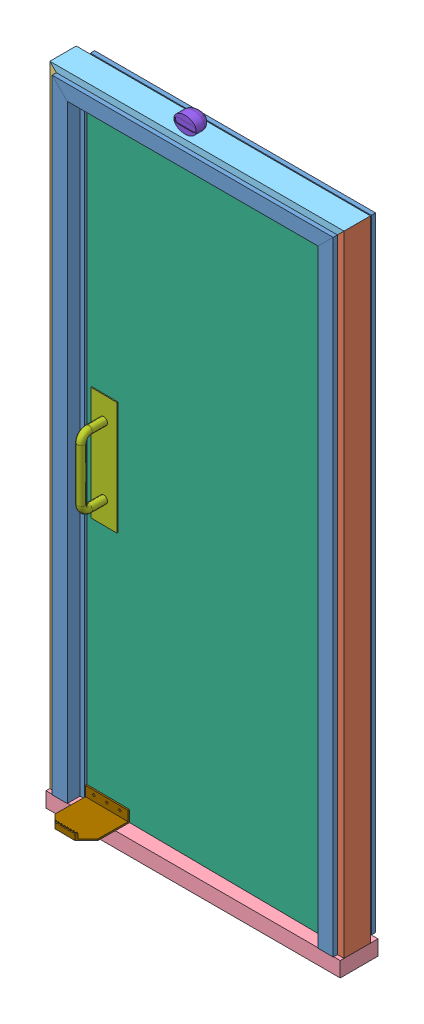
SolidWorks assembly Door 32, configuration Default. Lengths in mm.
Overall size (990.6 2284.92 238.36).
9 component instances, 9 part files, 24 mates.
Components (placement in the parent):
- Door Frame-1: Door Frame [Default] at (342.7653 -62.8092 1731.374) size (946.15 2098.68 142.88)
- Steel Tube Right-1: Steel Tube Right [Default] at (1180.9653 -62.8092 1671.049) size (63.5 2120.9 88.9)
- Steel Tube Left-1: Steel Tube Left [Default] at (253.8653 -62.8092 1671.049) size (63.5 2120.9 88.9)
- Steel Tube Base-1: Steel Tube Base [Default] at (253.8653 -113.6092 1772.649) size (990.6 50.8 127)
- Steel Tube Top-1: Steel Tube Top [Default] at (317.3653 1994.5908 1671.049) size (990.6 63.5 88.9)
- Door-1: Door [Default] at (-417.305 -65.202 1671.7811) x (0.999954 0 0.009626) z (-0.009626 0 0.999954) size (812.8 2032 44.45)
- DOOR32_HNDL-1: DOOR32_HNDL [Default] at (403.1251 953.1908 1724.1309) x (0.999954 0 0.009626) z (-0.009626 0 0.999954) size (88.9 381 139.7)
- Low Profile Forklift Red Light-1: Low Profile Forklift Red Light [Default] at (749.1653 2140.6408 1746.741) size (75.19 61.34 53.09)
- StepNPull-1: StepNPull [Default] at (342.8029 -62.8092 1723.5502) x (0.999954 0 0.009626) z (-0.009626 0 0.999954) size (144.78 38.1 144.78)
Mates (geometry in assembly coordinates):
- Coincident1: coincident anti-aligned: plane of Door Frame-1 through (317.3653 -62.8092 1645.649) normal (-1 0 0); plane of Steel Tube Left-1 through (317.3653 1994.5908 1759.949) normal (1 0 0)
- Coincident2: coincident anti-aligned: plane of Door Frame-1 through (1180.9653 2042.6333 1645.649) normal (1 0 0); plane of Steel Tube Right-1 through (1180.9653 -62.8092 1759.949) normal (-1 0 0)
- Coincident3: coincident anti-aligned: plane of Door Frame-1 through (1180.9653 2042.6333 1759.949) normal (0 0 -1); plane of Steel Tube Right-1 through (1180.9653 -62.8092 1759.949) normal (0 0 1)
- Coincident4: coincident anti-aligned: plane of Door Frame-1 through (269.3228 1994.5908 1645.649) normal (0 1 0); plane of Steel Tube Top-1 through (317.3653 1994.5908 1759.949) normal (0 -1 0)
- Coincident5: coincident anti-aligned: plane of Door Frame-1 through (269.3228 1994.5908 1759.949) normal (0 0 -1); plane of Steel Tube Top-1 through (317.3653 1994.5908 1759.949) normal (0 0 1)
- Coincident6: coincident anti-aligned: plane of Steel Tube Right-1 through (1180.9653 1994.5908 1759.949) normal (-0.707107 0.707107 0); plane of Steel Tube Top-1 through (1180.9653 1994.5908 1759.949) normal (0.707107 -0.707107 0)
- Coincident7: coincident aligned: line of Steel Tube Right-1 through (1244.4653 2058.0908 1759.949) axis (0 0 -1); line of Steel Tube Top-1 through (1244.4653 2058.0908 1759.949) axis (0 0 -1)
- Coincident8: coincident anti-aligned: plane of Door Frame-1 through (317.3653 -62.8092 1759.949) normal (0 0 -1); plane of Steel Tube Left-1 through (253.8653 -62.8092 1759.949) normal (0 0 1)
- Coincident9: coincident anti-aligned: plane of Steel Tube Left-1 through (253.8653 2058.0908 1759.949) normal (0.707107 0.707107 0); plane of Steel Tube Top-1 through (253.8653 2058.0908 1759.949) normal (-0.707107 -0.707107 0)
- Coincident10: coincident aligned: line of Steel Tube Left-1 through (253.8653 2058.0908 1759.949) axis (0 0 -1); line of Steel Tube Top-1 through (253.8653 2058.0908 1759.949) axis (0 0 -1)
- Coincident11: coincident anti-aligned: plane of Steel Tube Left-1 through (317.3653 -62.8092 1759.949) normal (0 -1 0); plane of Steel Tube Base-1 through (1244.4653 -62.8092 1772.649) normal (0 1 0)
- Coincident12: coincident anti-aligned: line of Steel Tube Left-1 through (253.8653 -62.8092 1759.949) axis (0 0 -1); line of Steel Tube Base-1 through (253.8653 -62.8092 1645.649) axis (0 0 1)
- Coincident14: coincident anti-aligned: line of Door Frame-1 through (1155.5653 1969.1908 1731.374) axis (0 -1 0); line of Door-1 through (1155.5653 -62.8092 1731.374) axis (0 1 0)
- Coincident15: coincident anti-aligned: plane of Steel Tube Base-1 through (1244.4653 -62.8092 1772.649) normal (0 1 0); plane of Door-1 through (342.8029 -62.8092 1723.5502) normal (0 -1 0)
- Coincident16: coincident aligned: line of Door Frame-1 through (1222.2403 -62.8092 1645.649) axis (-1 0 0); line of Steel Tube Base-1 through (1244.4653 -62.8092 1645.649) axis (-1 0 0)
- Concentric1: concentric aligned: cylinder of Door-1 through (403.553 953.1908 1679.6829) axis (-0.009626 0 0.999954) radius 26.9875; cylinder of DOOR32_HNDL-1 through (403.553 953.1908 1679.6829) axis (-0.009626 0 0.999954) radius 26.9875
- Coincident17: coincident aligned: circle of Door-1; circle of DOOR32_HNDL-1
- Parallel1: parallel aligned: line of Door-1 through (342.8029 -62.8092 1723.5502) axis (0.999954 0 0.009626); line of DOOR32_HNDL-1 through (358.6466 762.6908 1726.8778) axis (0.999954 0 0.009626)
- Coincident18: coincident anti-aligned: plane of Low Profile Forklift Red Light-1 through (749.1653 2140.6408 1746.741) normal (0 0 -1)
- Distance1: distance = 495.3 mm anti-aligned: plane of Low Profile Forklift Red Light-1 through (749.1653 2140.6408 1746.741) normal (1 0 0); plane of Steel Tube Left-1 through (253.8653 -62.8092 1759.949) normal (-1 0 0)
- Distance2: distance = 82.55 mm aligned: plane of Low Profile Forklift Red Light-1 through (749.1653 2140.6408 1746.741) normal (0 1 0); plane of Steel Tube Top-1 through (1244.4653 2058.0908 1759.949) normal (0 1 0)
- Coincident19: coincident aligned: plane of Door-1 through (-417.7329 -65.202 1716.2291) normal (-0.009626 0 0.999954); plane of StepNPull-1 through (342.8029 -62.8092 1723.5502) normal (-0.009626 0 0.999954)
- Coincident20: coincident anti-aligned: line of Door-1 through (342.8029 1969.1908 1723.5502) axis (0 -1 0); line of StepNPull-1 through (342.8029 -62.8092 1723.5502) axis (0 1 0)
- Coincident21: coincident aligned: line of Door-1 through (342.8029 -62.8092 1723.5502) axis (0.999954 0 0.009626); line of StepNPull-1 through (342.8029 -62.8092 1723.5502) axis (0.999954 0 0.009626)
